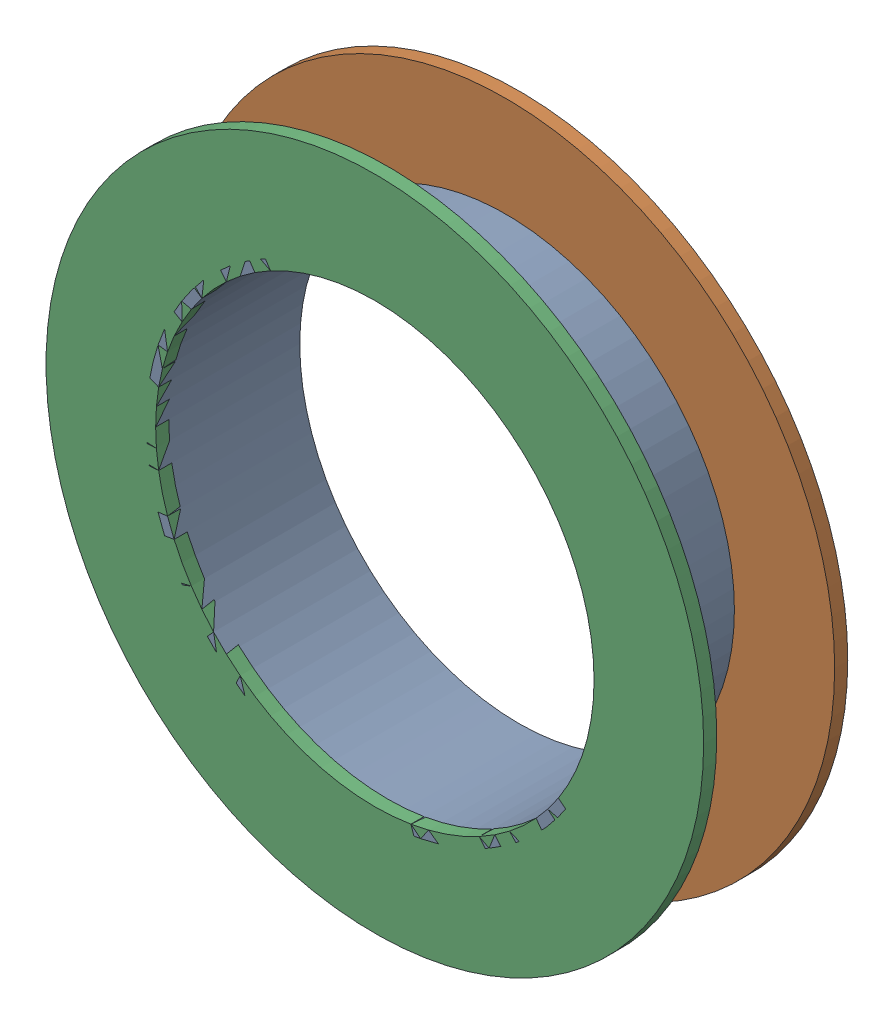
SolidWorks assembly Pad U1-3(28.178mm,4.578mm) on Multi-Layer, configuration Predeterminado. Lengths in mm.
Overall size (1.79 1.79 0.39).
6 component instances, 2 part files, 0 mates.
Components (placement in the parent):
- Pad Hole-1: Pad Hole [Predeterminado] at (28.1784 4.5777 -0.4013) size (1.24 1.24 0.39)
  - Pad Hole-Part-1-1: Pad Hole-Part-1 [Predeterminado] at origin size (1.24 1.24 0.39)
- Top Layer-1: Top Layer [Predeterminado] at (28.1784 4.5777 -0.4013) size (1.79 1.79 0.04)
  - Top Layer-Part-1-1: Top Layer-Part-1 [Predeterminado] at origin size (1.79 1.79 0.04)
- Top Layer-2: Top Layer [Predeterminado] at (28.1784 4.5777 -0.0457) size (1.79 1.79 0.04)
  - Top Layer-Part-1-1: Top Layer-Part-1 [Predeterminado] at origin size (1.79 1.79 0.04)
